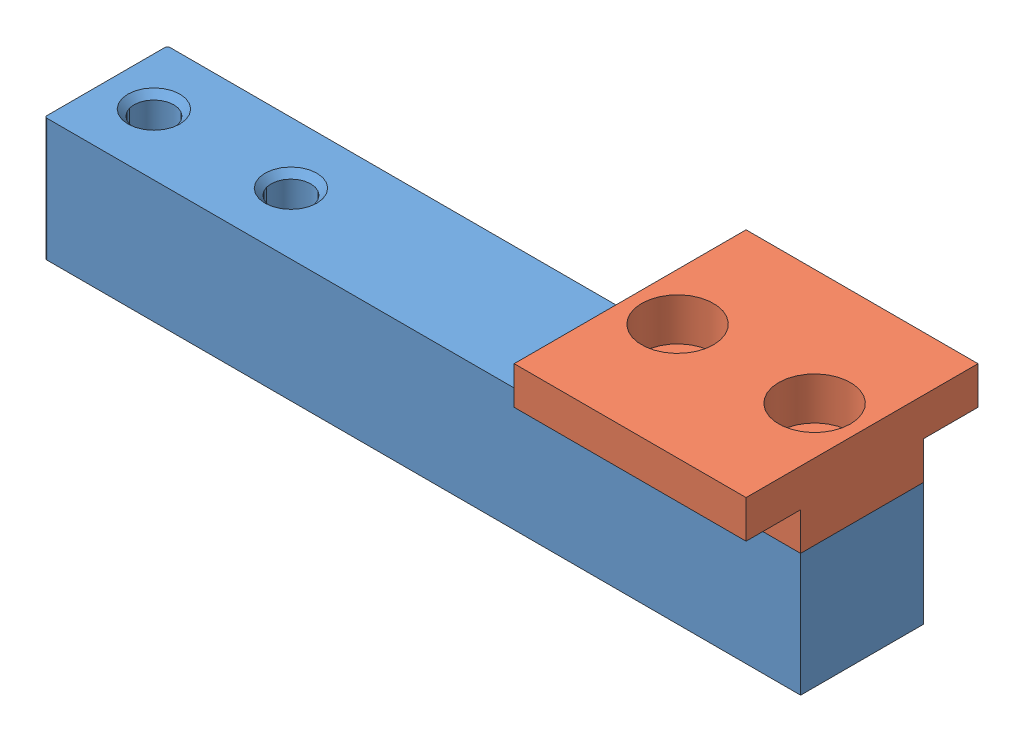
SolidWorks assembly Assem1, configuration Default. Lengths in mm.
Overall size (80 21 24.54).
2 component instances, 2 part files, 4 mates.
Components (placement in the parent):
- loadcell-1: loadcell [Default] at origin size (80 13 13)
- calibration stand-1: calibration stand [Default] at (0 13 0) x (1 0 0) z (0 1 0) size (24.54 24.54 8)
Mates (geometry in assembly coordinates):
- InPlace1: in place: plane of loadcell-1 through (0 13 0) normal (0 1 0); plane of calibration stand-1 through (0 13 0) normal (0 1 0); moOrthogonalPlaneRef_w of loadcell-1 through (0 13 0) normal (0 1 0); plane of calibration stand-1 through (0 13 0) normal (0 0 -1); plane of loadcell-1 through (0 13 0) normal (0 1 0); plane of calibration stand-1 through (0 13 0) normal (1 0 0); plane of loadcell-1 through (0 13 0) normal (0 1 0); unknown of calibration stand-1
- Coincident1: coincident aligned: plane of ?; plane of ?
- Coincident2: coincident aligned: moOrthogonalPlaneRef_w of loadcell-1 through (0 13 0) normal (0 0 -1); plane of Part1^Assem1-1 through (0 13 0) normal (0 0 -1)
- Coincident3: coincident anti-aligned: moOrthogonalPlaneRef_w of loadcell-1 through (0 13 0) normal (-1 0 0); plane of Part1^Assem1-1 through (0 13 0) normal (1 0 0)
